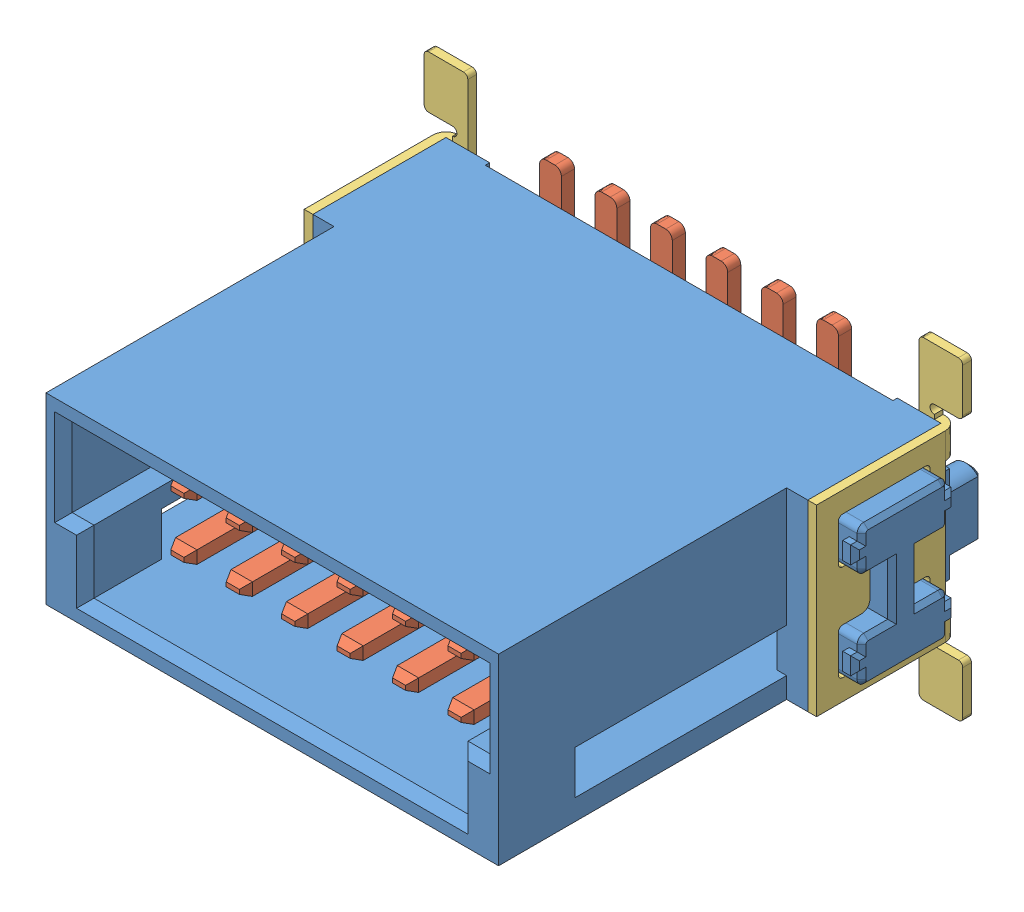
SolidWorks assembly m55-7021242_asm, configuration Default. Lengths in mm.
Overall size (12.7 7.2 10.6).
16 component instances, 3 part files, 0 mates.
Components (placement in the parent):
- m55-7021242_asm.stp-1: m55-7021242_asm.stp [Default] at origin size (12.7 7.2 10.6)
  - M55-70212_MOULD.stp-1: M55-70212_MOULD.stp [Default] at origin size (12.7 4.2 10.6)
  - M55-702_CONTACT.stp-1: M55-702_CONTACT.stp [Default] at (-3.175 -0.785 8.85) x (1 0 0) z (0 1 0) size (1.1 8.85 2.42)
  - M55-702_CONTACT.stp-2: M55-702_CONTACT.stp [Default] at (-1.905 -0.785 8.85) x (1 0 0) z (0 1 0) size (1.1 8.85 2.42)
  - M55-702_CONTACT.stp-3: M55-702_CONTACT.stp [Default] at (-0.635 -0.785 8.85) x (1 0 0) z (0 1 0) size (1.1 8.85 2.42)
  - M55-702_CONTACT.stp-4: M55-702_CONTACT.stp [Default] at (0.635 -0.785 8.85) x (1 0 0) z (0 1 0) size (1.1 8.85 2.42)
  - M55-702_CONTACT.stp-5: M55-702_CONTACT.stp [Default] at (1.905 -0.785 8.85) x (1 0 0) z (0 1 0) size (1.1 8.85 2.42)
  - M55-702_CONTACT.stp-6: M55-702_CONTACT.stp [Default] at (3.175 -0.785 8.85) x (1 0 0) z (0 1 0) size (1.1 8.85 2.42)
  - M55-702_CONTACT.stp-7: M55-702_CONTACT.stp [Default] at (-3.175 0.785 8.85) x (-1 0 0) z (0 -1 0) size (1.1 8.85 2.42)
  - M55-702_CONTACT.stp-8: M55-702_CONTACT.stp [Default] at (-1.905 0.785 8.85) x (-1 0 0) z (0 -1 0) size (1.1 8.85 2.42)
  - M55-702_CONTACT.stp-9: M55-702_CONTACT.stp [Default] at (-0.635 0.785 8.85) x (-1 0 0) z (0 -1 0) size (1.1 8.85 2.42)
  - M55-702_CONTACT.stp-10: M55-702_CONTACT.stp [Default] at (0.635 0.785 8.85) x (-1 0 0) z (0 -1 0) size (1.1 8.85 2.42)
  - M55-702_CONTACT.stp-11: M55-702_CONTACT.stp [Default] at (1.905 0.785 8.85) x (-1 0 0) z (0 -1 0) size (1.1 8.85 2.42)
  - M55-702_CONTACT.stp-12: M55-702_CONTACT.stp [Default] at (3.175 0.785 8.85) x (-1 0 0) z (0 -1 0) size (1.1 8.85 2.42)
  - M55-700_STRAP.stp-1: M55-700_STRAP.stp [Default] at (-5.67 0 0) x (1 0 0) z (0 -1 0) size (1 3.25 7.2)
  - M55-700_STRAP.stp-2: M55-700_STRAP.stp [Default] at (5.67 0 0) x (-1 0 0) z (0 1 0) size (1 3.25 7.2)
